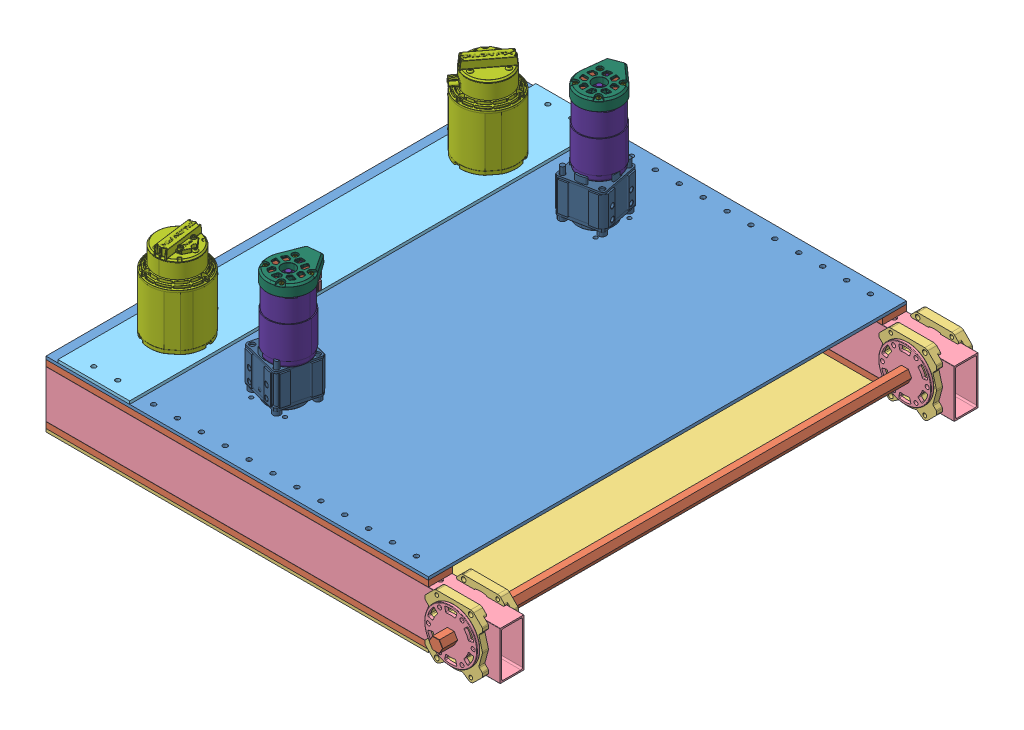
SolidWorks assembly ShooterAssem5, configuration Default. Lengths in mm.
Overall size (500 222.05 558.8).
72 component instances, 22 part files, 84 mates.
Components (placement in the parent):
- ShooterPlate5-1: ShooterPlate5 [Default] at (-92.3523 325.8959 643.1212) size (406.4 3.17 508)
- ThickStick-3: ThickStick [Default] at (-92.3523 262.3959 643.1212) size (406.4 6.35 25.4)
- ThickStick-1: ThickStick [Default] at (-92.3523 319.5459 643.1212) size (406.4 6.35 25.4)
- ThickStick-2: ThickStick [Default] at (-92.3523 262.3959 160.5212) size (406.4 6.35 25.4)
- ThickStick-4: ThickStick [Default] at (-92.3523 319.5459 160.5212) size (406.4 6.35 25.4)
- ShooterPlate4-1: ShooterPlate4 [Default] at (-257.4523 259.2209 643.1212) size (406.4 3.17 508)
- side-1: side [Default] at (364.8477 294.1459 147.8212) x (0 0 1) z (-1 0 0) size (25.4 50.8 482.6)
- side-2: side [Default] at (364.8477 294.1459 630.4212) x (0 0 1) z (-1 0 0) size (25.4 50.8 482.6)
- Motor support2-1: Motor support2 [Default] at (-41.5523 329.0709 389.1212) x (0 0 1) z (-1 0 0) size (508 3.17 76.2)
- am-4119 8mm Key Hub.step-1: am-4119 8mm Key Hub.step [Default] at (-49.7507 310.7834 262.3625) x (0.806664 0 -0.591011) z (0 1 0) size (58.55 52.17 25.4)
- am-4119 8mm Key Hub.step-2: am-4119 8mm Key Hub.step [Default] at (-13.8443 310.7834 526.4806) x (-0.998309 0 0.058123) z (0 1 0) size (58.55 52.17 25.4)
- Falcon 500.step-1: Falcon 500.step [Default] at (-41.5523 392.9959 224.0212) x (-0.923728 0 0.383049) z (0 -1 0) size (62.05 60 125.3)
- Falcon 500.step-2: Falcon 500.step [Default] at (-41.5523 392.9959 554.2212) x (0.381645 0 -0.924309) z (0 -1 0) size (62.05 60 125.3)
- 4in hex stealth wheel-1: 4in hex stealth wheel [Default] at (-41.5523 290.5093 554.2212) x (0 -1 0) z (-0.448819 0 0.893623) size (25.4 101.6 101.6)
  - 4in Wheel Intergreated Hub 500 HEX.STEP-1: 4in Wheel Intergreated Hub 500 HEX.STEP [Default] at origin size (25.4 92.71 92.71)
  - 4in Tread.STEP-1: 4in Tread.STEP [Default] at origin size (25.4 101.6 101.6)
- 4in hex stealth wheel-2: 4in hex stealth wheel [Default] at (72.733 290.5093 554.2466) x (0 -1 0) z (-0.5 0 0.866025) size (25.4 101.6 101.6)
  - 4in Wheel Intergreated Hub 500 HEX.STEP-1: 4in Wheel Intergreated Hub 500 HEX.STEP [Default] at origin size (25.4 92.71 92.71)
  - 4in Tread.STEP-1: 4in Tread.STEP [Default] at origin size (25.4 101.6 101.6)
- 4in hex stealth wheel-3: 4in hex stealth wheel [Default] at (72.7256 290.5093 224.0405) x (0 -1 0) z (0.194202 0 0.980962) size (25.4 101.6 101.6)
  - 4in Wheel Intergreated Hub 500 HEX.STEP-1: 4in Wheel Intergreated Hub 500 HEX.STEP [Default] at origin size (25.4 92.71 92.71)
  - 4in Tread.STEP-1: 4in Tread.STEP [Default] at origin size (25.4 101.6 101.6)
- 4in hex stealth wheel-4: 4in hex stealth wheel [Default] at (-41.5523 290.5093 224.0212) x (0 -1 0) z (0.108499 0 0.994097) size (25.4 101.6 101.6)
  - 4in Wheel Intergreated Hub 500 HEX.STEP-1: 4in Wheel Intergreated Hub 500 HEX.STEP [Default] at origin size (25.4 92.71 92.71)
  - 4in Tread.STEP-1: 4in Tread.STEP [Default] at origin size (25.4 101.6 101.6)
- 4-1 Banebots-1: 4-1 Banebots [Default] at (72.7475 371.6159 224.0202) x (-0.194202 0 -0.980962) z (0 -1 0) size (47.62 47.62 76.19)
- 4-1 Banebots-2: 4-1 Banebots [Default] at (72.7467 371.6159 554.2209) x (-0.969356 0 -0.245662) z (0 -1 0) size (47.62 47.62 76.19)
- 775pro.step-1: 775pro.step [Default] at (71.7936 373.6479 219.2017) x (-0.934395 0 0.356239) z (0 -1 0) size (44.99 55.15 90.45)
  - 217-6457-000 Rev2.step-1: 217-6457-000 Rev2.step [Default] at (0 0 -66.1) x (1 0 0) z (0 1 0) size (44.99 33.26 55.15)
    - 217-6457-900 Rev1.step-1: 217-6457-900 Rev1.step [Default] at (0 5.3622 0) x (-1 0 0.000693) z (0.000693 0 1) size (41.5 28.13 51.51)
      - 217-6457-901 Rev3_Instruction Config.step-1: 217-6457-901 Rev3_Instruction Config.step [Default] at origin size (41.5 2.36 51.5)
      - 30-45BBS Rev1_SHORTENED CONTACT.step-1: 30-45BBS Rev1_SHORTENED CONTACT.step [Default] at (3.95 14.4494 26.711) x (0 1 0) z (0 0 -1) size (26 3.6 2)
      - 30-45BBS Rev1_SHORTENED CONTACT.step-2: 30-45BBS Rev1_SHORTENED CONTACT.step [Default] at (-3.9748 14.4494 26.711) x (0 1 0) z (0 0 -1) size (26 3.6 2)
      - PA45XX-X Rev1.step-1: PA45XX-X Rev1.step [Default] at (-8.4198 2.3622 73.1531) x (0 1 0) z (-1 0 0) size (24.71 8.41 8.41)
      - PA45XX-X Rev1.step-2: PA45XX-X Rev1.step [Default] at (-0.495 2.3622 73.1531) x (0 1 0) z (-1 0 0) size (24.71 8.41 8.41)
    - 217-6457-001 Rev4.step-1: 217-6457-001 Rev4.step [Default] at origin size (41.49 7.8 41.49)
    - 217-6457-002 Rev7.step-1: 217-6457-002 Rev7.step [Default] at (0 0.05 0) size (44.99 11.5 55.15)
    - 217-9191-008 Rev1.step-1: 217-9191-008 Rev1.step [Default] at (81.4247 7.8 32.3804) x (-0.560945 0 -0.827853) z (0 1 0) size (4.2 4.2 11.81)
    - 217-9191-008 Rev1.step-2: 217-9191-008 Rev1.step [Default] at (32.3804 7.8 -81.4247) x (-0.827853 0 0.560945) z (0 1 0) size (4.2 4.2 11.81)
    - 217-9191-008 Rev1.step-3: 217-9191-008 Rev1.step [Default] at (-81.4247 7.8 -32.3804) x (0.560945 0 0.827853) z (0 1 0) size (4.2 4.2 11.81)
    - 217-9191-008 Rev1.step-4: 217-9191-008 Rev1.step [Default] at (-32.3804 7.8 81.4247) x (0.827853 0 -0.560945) z (0 1 0) size (4.2 4.2 11.81)
  - 217-4347-000 Rev2.step-1: 217-4347-000 Rev2.step [Default] x (0 0 -1) z (-1 0 0) size (88 44.3 44.3)
- 775pro.step-2: 775pro.step [Default] at (77.5101 373.6479 555.4281) x (-0.994351 0 0.106139) z (0 -1 0) size (44.99 55.15 90.45)
  - 217-6457-000 Rev2.step-1: 217-6457-000 Rev2.step [Default] at (0 0 -66.1) x (1 0 0) z (0 1 0) size (44.99 33.26 55.15)
    - 217-6457-900 Rev1.step-1: 217-6457-900 Rev1.step [Default] at (0 5.3622 0) x (-1 0 0.000693) z (0.000693 0 1) size (41.5 28.13 51.51)
      - 217-6457-901 Rev3_Instruction Config.step-1: 217-6457-901 Rev3_Instruction Config.step [Default] at origin size (41.5 2.36 51.5)
      - 30-45BBS Rev1_SHORTENED CONTACT.step-1: 30-45BBS Rev1_SHORTENED CONTACT.step [Default] at (3.95 14.4494 26.711) x (0 1 0) z (0 0 -1) size (26 3.6 2)
      - 30-45BBS Rev1_SHORTENED CONTACT.step-2: 30-45BBS Rev1_SHORTENED CONTACT.step [Default] at (-3.9748 14.4494 26.711) x (0 1 0) z (0 0 -1) size (26 3.6 2)
      - PA45XX-X Rev1.step-1: PA45XX-X Rev1.step [Default] at (-8.4198 2.3622 73.1531) x (0 1 0) z (-1 0 0) size (24.71 8.41 8.41)
      - PA45XX-X Rev1.step-2: PA45XX-X Rev1.step [Default] at (-0.495 2.3622 73.1531) x (0 1 0) z (-1 0 0) size (24.71 8.41 8.41)
    - 217-6457-001 Rev4.step-1: 217-6457-001 Rev4.step [Default] at origin size (41.49 7.8 41.49)
    - 217-6457-002 Rev7.step-1: 217-6457-002 Rev7.step [Default] at (0 0.05 0) size (44.99 11.5 55.15)
    - 217-9191-008 Rev1.step-1: 217-9191-008 Rev1.step [Default] at (81.4247 7.8 32.3804) x (-0.560945 0 -0.827853) z (0 1 0) size (4.2 4.2 11.81)
    - 217-9191-008 Rev1.step-2: 217-9191-008 Rev1.step [Default] at (32.3804 7.8 -81.4247) x (-0.827853 0 0.560945) z (0 1 0) size (4.2 4.2 11.81)
    - 217-9191-008 Rev1.step-3: 217-9191-008 Rev1.step [Default] at (-81.4247 7.8 -32.3804) x (0.560945 0 0.827853) z (0 1 0) size (4.2 4.2 11.81)
    - 217-9191-008 Rev1.step-4: 217-9191-008 Rev1.step [Default] at (-32.3804 7.8 81.4247) x (0.827853 0 -0.560945) z (0 1 0) size (4.2 4.2 11.81)
  - 217-4347-000 Rev2.step-1: 217-4347-000 Rev2.step [Default] x (0 0 -1) z (-1 0 0) size (88 44.3 44.3)
- 4in hex shaft-1: 4in hex shaft [Default] at (72.7477 330.8489 224.0212) x (0.752436 0 -0.658665) z (0 -1 0) size (14.66 12.7 101.6)
- 4in hex shaft-2: 4in hex shaft [Default] at (72.7477 330.8489 554.2212) x (-0.969356 0 -0.245662) z (0 -1 0) size (14.66 12.7 101.6)
- am-2986 FR8ZZ Hex Bearing.step-1: am-2986 FR8ZZ Hex Bearing.step [Default] at (72.7477 255.9925 554.2212) x (0.969356 0 0.245662) z (0 1 0) size (31.12 31.12 7.93)
- am-2986 FR8ZZ Hex Bearing.step-2: am-2986 FR8ZZ Hex Bearing.step [Default] at (72.7477 322.6675 554.2212) x (1 0 0) z (0 1 0) size (31.12 31.12 7.93)
- am-2986 FR8ZZ Hex Bearing.step-3: am-2986 FR8ZZ Hex Bearing.step [Default] at (72.7477 322.6675 224.0212) x (0.194202 0 0.980962) z (0 1 0) size (31.12 31.12 7.93)
- am-2986 FR8ZZ Hex Bearing.step-4: am-2986 FR8ZZ Hex Bearing.step [Default] at (72.7477 255.9925 224.0212) x (0.946639 0 0.322297) z (0 1 0) size (31.12 31.12 7.93)
- shooteraxle-1: shooteraxle [Default] at (347.36 295.7842 109.7212) size (14.66 12.7 558.8)
- VersaBlock V2 (217-6111).step-1: VersaBlock V2 (217-6111).step [Default] at (347.3674 295.7969 131.9462) x (1 0 0) z (0 0 -1) size (61.04 66.67 9.53)
- VersaBlock V2 (217-6111).step-2: VersaBlock V2 (217-6111).step [Default] at (347.3674 295.7969 614.5462) x (1 0 0) z (0 0 -1) size (61.04 66.67 9.53)
- VersaBlock V2 (217-6111).step-3: VersaBlock V2 (217-6111).step [Default] at (347.3674 295.7969 646.2962) x (-1 0 0) z (0 0 1) size (61.04 66.67 9.53)
- VersaBlock V2 (217-6111).step-4: VersaBlock V2 (217-6111).step [Default] at (347.3674 295.7969 163.6962) x (-1 0 0) z (0 0 1) size (61.04 66.67 9.53)
- 1_2” Hex Bore Aluminum VersaHub (217-2592).step-1: 1_2” Hex Bore Aluminum VersaHub (217-2592).step [Default] at (347.3674 295.7969 138.2962) x (0 0 -1) z (0.866025 -0.5 0) size (12.7 55.88 55.88)
- 1_2” Hex Bore Aluminum VersaHub (217-2592).step-2: 1_2” Hex Bore Aluminum VersaHub (217-2592).step [Default] at (347.3674 295.7969 157.3462) x (0 0 1) z (-0.866025 -0.5 0) size (12.7 55.88 55.88)
- 1_2” Hex Bore Aluminum VersaHub (217-2592).step-3: 1_2” Hex Bore Aluminum VersaHub (217-2592).step [Default] at (347.3674 295.7969 620.8962) x (0 0 -1) z (0.866025 0.5 0) size (12.7 55.88 55.88)
- 1_2” Hex Bore Aluminum VersaHub (217-2592).step-4: 1_2” Hex Bore Aluminum VersaHub (217-2592).step [Default] at (347.3674 295.7969 639.9462) x (0 0 1) z (-0.866025 0.5 0) size (12.7 55.88 55.88)
Mates (geometry in assembly coordinates):
- Coincident2: coincident aligned: plane of ShooterPlate5-1 through (-92.3523 329.0709 643.1212) normal (-1 0 0); plane of side-2 through (-92.3523 319.2919 642.8672) normal (-1 0 0)
- Coincident3: coincident aligned: plane of ShooterPlate5-1 through (-92.3523 329.0709 643.1212) normal (0 0 1); plane of side-2 through (390.2477 319.2919 643.1212) normal (0 0 1)
- Coincident4: coincident anti-aligned: plane of ShooterPlate5-1 through (-92.3523 325.8959 643.1212) normal (0 -1 0); plane of ThickStick-1 through (-92.3523 325.8959 643.1212) normal (0 1 0)
- Coincident5: coincident aligned: plane of ShooterPlate5-1 through (314.0477 329.0709 643.1212) normal (1 0 0); plane of ThickStick-1 through (314.0477 325.8959 643.1212) normal (1 0 0)
- Coincident6: coincident aligned: plane of ShooterPlate5-1 through (-92.3523 329.0709 643.1212) normal (0 0 1); plane of ThickStick-1 through (-92.3523 325.8959 643.1212) normal (0 0 1)
- Coincident7: coincident anti-aligned: plane of ThickStick-1 through (-92.3523 319.5459 643.1212) normal (0 -1 0); plane of side-2 through (390.2477 319.5459 617.9752) normal (0 1 0)
- Coincident8: coincident anti-aligned: plane of ThickStick-3 through (-92.3523 268.7459 643.1212) normal (0 1 0); plane of side-2 through (390.2477 268.7459 642.8672) normal (0 -1 0)
- Coincident9: coincident aligned: plane of ThickStick-3 through (-92.3523 268.7459 643.1212) normal (0 0 1); plane of side-2 through (390.2477 319.2919 643.1212) normal (0 0 1)
- Coincident11: coincident aligned: plane of ThickStick-1 through (-92.3523 325.8959 643.1212) normal (-1 0 0); plane of ThickStick-3 through (-92.3523 268.7459 643.1212) normal (-1 0 0)
- Coincident12: coincident anti-aligned: plane of ThickStick-3 through (-92.3523 262.3959 643.1212) normal (0 -1 0); plane of ShooterPlate4-1 through (-257.4523 262.3959 643.1212) normal (0 1 0)
- Coincident13: coincident aligned: plane of ShooterPlate5-1 through (-92.3523 329.0709 643.1212) normal (0 0 1); plane of ShooterPlate4-1 through (-257.4523 262.3959 643.1212) normal (0 0 1)
- Coincident14: coincident aligned: plane of ThickStick-3 through (314.0477 268.7459 643.1212) normal (1 0 0); plane of ShooterPlate4-1 through (314.0477 262.3959 643.1212) normal (1 0 0)
- Coincident15: coincident anti-aligned: plane of ShooterPlate5-1 through (-92.3523 325.8959 643.1212) normal (0 -1 0); plane of ThickStick-4 through (-92.3523 325.8959 160.5212) normal (0 1 0)
- Coincident16: coincident aligned: plane of ShooterPlate5-1 through (-92.3523 329.0709 643.1212) normal (-1 0 0); plane of ThickStick-4 through (-92.3523 325.8959 160.5212) normal (-1 0 0)
- Coincident17: coincident anti-aligned: plane of ThickStick-4 through (-92.3523 319.5459 160.5212) normal (0 -1 0); plane of side-1 through (390.2477 319.5459 135.3752) normal (0 1 0)
- Coincident18: coincident aligned: plane of ShooterPlate5-1 through (-92.3523 329.0709 135.1212) normal (0 0 -1); plane of ThickStick-4 through (-92.3523 325.8959 135.1212) normal (0 0 -1)
- Coincident19: coincident aligned: plane of ThickStick-4 through (-92.3523 325.8959 135.1212) normal (0 0 -1); plane of side-1 through (390.2477 268.9999 135.1212) normal (0 0 -1)
- Coincident20: coincident aligned: plane of ThickStick-4 through (-92.3523 325.8959 160.5212) normal (-1 0 0); plane of side-1 through (-92.3523 319.2919 160.2672) normal (-1 0 0)
- Coincident21: coincident anti-aligned: plane of ThickStick-2 through (-92.3523 262.3959 160.5212) normal (0 -1 0); plane of ShooterPlate4-1 through (-257.4523 262.3959 643.1212) normal (0 1 0)
- Coincident22: coincident aligned: plane of ThickStick-2 through (-92.3523 268.7459 135.1212) normal (0 0 -1); plane of side-1 through (390.2477 268.9999 135.1212) normal (0 0 -1)
- Coincident23: coincident aligned: plane of ShooterPlate5-1 through (-92.3523 329.0709 643.1212) normal (-1 0 0); plane of ThickStick-2 through (-92.3523 268.7459 160.5212) normal (-1 0 0)
- Coincident24: coincident anti-aligned: plane of ShooterPlate5-1 through (-92.3523 329.0709 643.1212) normal (0 1 0); plane of Motor support2-1 through (-41.5523 329.0709 389.1212) normal (0 -1 0)
- Coincident25: coincident aligned: plane of side-1 through (390.2477 268.9999 135.1212) normal (0 0 -1); plane of Motor support2-1 through (-79.6523 332.2459 135.1212) normal (0 0 -1)
- Concentric1: concentric aligned: cylinder of ShooterPlate5-1 through (-41.5523 325.8959 224.0212) axis (0 1 0) radius 14.2875; cylinder of Motor support2-1 through (-41.5523 329.0709 224.0212) axis (0 1 0) radius 12.7
- Concentric5: concentric anti-aligned: cylinder of Motor support2-1 through (-41.5523 329.0709 224.0212) axis (0 1 0) radius 12.7; cylinder of am-4119 8mm Key Hub.step-1 through (-41.5523 326.6584 224.0212) axis (0 -1 0) radius 11.1125
- Coincident30: coincident anti-aligned: plane of am-4119 8mm Key Hub.step-1 through (-41.5523 304.4334 224.0212) normal (0 -1 0); plane of 4in hex stealth wheel-4/4in Wheel Intergreated Hub 500 HEX.STEP-1 through (-35.2398 304.4334 223.3322) normal (0 1 0)
- Concentric6: concentric anti-aligned: cylinder of am-4119 8mm Key Hub.step-1 through (-60.761 310.7834 238.0946) axis (0 -1 0) radius 2.5527; cylinder of 4in hex stealth wheel-4/4in Wheel Intergreated Hub 500 HEX.STEP-1 through (-60.761 279.0334 238.0946) axis (0 1 0) radius 2.0193
- Concentric7: concentric anti-aligned: cylinder of am-4119 8mm Key Hub.step-1 through (-38.9687 310.7834 247.6931) axis (0 -1 0) radius 2.5527; cylinder of 4in hex stealth wheel-4/4in Wheel Intergreated Hub 500 HEX.STEP-1 through (-38.9687 279.0334 247.6931) axis (0 1 0) radius 2.0193
- Coincident31: coincident anti-aligned: plane of am-4119 8mm Key Hub.step-2 through (-41.5523 304.4334 554.2212) normal (0 -1 0); plane of 4in hex stealth wheel-1/4in Wheel Intergreated Hub 500 HEX.STEP-1 through (-35.8778 304.4334 557.0712) normal (0 1 0)
- Concentric8: concentric anti-aligned: cylinder of am-4119 8mm Key Hub.step-2 through (-65.3245 310.7834 555.6052) axis (0 -1 0) radius 2.5527; cylinder of 4in hex stealth wheel-1/4in Wheel Intergreated Hub 500 HEX.STEP-1 through (-65.3245 279.0334 555.6052) axis (0 1 0) radius 2.0193
- Concentric9: concentric anti-aligned: cylinder of am-4119 8mm Key Hub.step-2 through (-52.2398 310.7834 575.5005) axis (0 -1 0) radius 2.5527; cylinder of 4in hex stealth wheel-1/4in Wheel Intergreated Hub 500 HEX.STEP-1 through (-52.2398 279.0334 575.5005) axis (0 1 0) radius 2.0193
- Concentric10: concentric anti-aligned: cylinder of ShooterPlate5-1 through (72.7477 325.8959 224.0212) axis (0 1 0) radius 14.2875; cylinder of am-2986 FR8ZZ Hex Bearing.step-3 through (72.7477 330.5949 224.0212) axis (0 -1 0) radius 14.2875
- Coincident39: coincident anti-aligned: plane of ShooterPlate5-1 through (-92.3523 329.0709 643.1212) normal (0 1 0); plane of am-2986 FR8ZZ Hex Bearing.step-3 through (75.4607 329.0709 237.7252) normal (0 -1 0)
- Concentric11: concentric anti-aligned: cylinder of ShooterPlate5-1 through (72.7477 325.8959 554.2212) axis (0 1 0) radius 14.2875; cylinder of am-2986 FR8ZZ Hex Bearing.step-2 through (72.7477 330.5949 554.2212) axis (0 -1 0) radius 14.2875
- Coincident40: coincident anti-aligned: plane of ShooterPlate5-1 through (-92.3523 329.0709 643.1212) normal (0 1 0); plane of am-2986 FR8ZZ Hex Bearing.step-2 through (86.7177 329.0709 554.2212) normal (0 -1 0)
- Concentric12: concentric anti-aligned: cylinder of ShooterPlate4-1 through (72.7477 259.2209 554.2212) axis (0 1 0) radius 14.2875; cylinder of am-2986 FR8ZZ Hex Bearing.step-1 through (72.7477 263.9199 554.2212) axis (0 -1 0) radius 14.2875
- Coincident41: coincident anti-aligned: plane of ShooterPlate4-1 through (-257.4523 262.3959 643.1212) normal (0 1 0); plane of am-2986 FR8ZZ Hex Bearing.step-1 through (86.2896 262.3959 557.6531) normal (0 -1 0)
- Concentric13: concentric anti-aligned: cylinder of ShooterPlate4-1 through (72.7477 259.2209 224.0212) axis (0 1 0) radius 14.2875; cylinder of am-2986 FR8ZZ Hex Bearing.step-4 through (72.7477 263.9199 224.0212) axis (0 -1 0) radius 14.2875
- Coincident42: coincident anti-aligned: plane of ShooterPlate4-1 through (-257.4523 262.3959 643.1212) normal (0 1 0); plane of am-2986 FR8ZZ Hex Bearing.step-4 through (85.9723 262.3959 228.5236) normal (0 -1 0)
- Coincident44: coincident anti-aligned: plane of 4-1 Banebots-1 through (67.2306 330.8559 228.8507) normal (-0.980962 0 0.194202); plane of am-2986 FR8ZZ Hex Bearing.step-3 through (67.2306 330.5949 228.8507) normal (0.980962 0 -0.194202)
- Coincident49: coincident aligned: plane of 4in hex stealth wheel-3/4in Wheel Intergreated Hub 500 HEX.STEP-1 through (78.9547 304.4334 222.8073) normal (0 1 0); plane of 4in hex stealth wheel-4/4in Wheel Intergreated Hub 500 HEX.STEP-1 through (-35.2398 304.4334 223.3322) normal (0 1 0)
- Coincident50: coincident aligned: plane of 4in hex stealth wheel-1/4in Wheel Intergreated Hub 500 HEX.STEP-1 through (-35.8778 304.4334 557.0712) normal (0 1 0); plane of 4in hex stealth wheel-2/4in Wheel Intergreated Hub 500 HEX.STEP-1 through (78.2323 304.4334 557.4216) normal (0 1 0)
- Coincident53: coincident anti-aligned: plane of 4in hex shaft-2 through (67.6339 229.2489 559.4759) normal (-0.245662 0 0.969356); plane of am-2986 FR8ZZ Hex Bearing.step-1 through (74.7416 263.9199 561.2772) normal (0.245662 0 -0.969356)
- Coincident54: coincident anti-aligned: plane of 4in hex shaft-2 through (65.6401 229.2489 552.4199) normal (-0.962318 0 0.271928); plane of am-2986 FR8ZZ Hex Bearing.step-1 through (67.6339 263.9199 559.4759) normal (0.962318 0 -0.271928)
- Tangent9: tangent: plane of assembly; face of 4-1 Banebots-2; plane of 4in hex shaft-2 through (72.7477 330.8489 554.2212) normal (0 1 0)
- Coincident55: coincident aligned: plane of 4-1 Banebots-2 through (65.6401 330.8559 552.4199) normal (-0.716656 0 -0.697427); plane of 4in hex shaft-2 through (70.7538 229.2489 547.1651) normal (-0.716656 0 -0.697427)
- Coincident56: coincident aligned: plane of 4-1 Banebots-2 through (70.7538 330.8559 547.1651) normal (0.245662 0 -0.969356); plane of 4in hex shaft-2 through (77.8615 229.2489 548.9664) normal (0.245662 0 -0.969356)
- Tangent10: tangent: plane of assembly; face of 4-1 Banebots-2; plane of am-2986 FR8ZZ Hex Bearing.step-2 through (88.3052 330.5949 554.2212) normal (0 1 0)
- Tangent11: tangent: plane of assembly; face of 4-1 Banebots-1; plane of 4in hex shaft-1 through (72.7477 330.8489 224.0212) normal (0 1 0)
- Coincident57: coincident aligned: plane of 4-1 Banebots-1 through (65.8066 330.8559 221.658) normal (-0.658665 0 -0.752436); plane of 4in hex shaft-1 through (71.3238 229.2489 216.8284) normal (-0.658665 0 -0.752436)
- Coincident58: coincident aligned: plane of 4-1 Banebots-1 through (67.2306 330.8559 228.8507) normal (-0.980962 0 0.194202); plane of 4in hex shaft-1 through (65.8066 229.2489 221.658) normal (-0.980962 0 0.194202)
- Tangent12: tangent: plane of assembly; face of 4-1 Banebots-1; plane of am-2986 FR8ZZ Hex Bearing.step-3 through (75.769 330.5949 239.2825) normal (0 1 0)
- Coincident60: coincident anti-aligned: plane of 4in hex shaft-1 through (79.6888 229.2489 226.3843) normal (0.980962 0 -0.194202); plane of am-2986 FR8ZZ Hex Bearing.step-4 through (78.2648 263.9199 219.1916) normal (-0.980962 0 0.194202)
- Coincident61: coincident anti-aligned: plane of 4in hex shaft-1 through (74.1717 229.2489 231.2139) normal (0.658665 0 0.752436); plane of am-2986 FR8ZZ Hex Bearing.step-4 through (79.6888 263.9199 226.3843) normal (-0.658665 0 -0.752436)
- Coincident62: coincident anti-aligned: plane of 4in hex stealth wheel-3/4in Wheel Intergreated Hub 500 HEX.STEP-1 through (71.296 304.4334 216.819) normal (-0.322297 0 0.946639); plane of 4in hex shaft-1 through (78.2648 229.2489 219.1916) normal (0.322297 0 -0.946639)
- Coincident63: coincident anti-aligned: plane of 4in hex stealth wheel-3/4in Wheel Intergreated Hub 500 HEX.STEP-1 through (78.2648 304.4334 219.1916) normal (-0.980962 0 0.194202); plane of 4in hex shaft-1 through (79.6888 229.2489 226.3843) normal (0.980962 0 -0.194202)
- Distance1: distance = 25.4 mm: plane of side-1 through (390.2477 268.9999 135.1212) normal (0 0 -1); plane of shooteraxle-1 through (347.36 295.7842 109.7212) normal (0 0 -1)
- Coincident72: coincident anti-aligned: plane of side-2 through (390.2477 319.2919 643.1212) normal (0 0 1); plane of VersaBlock V2 (217-6111).step-3 through (347.3674 295.7969 643.1212) normal (0 0 -1)
- Coincident73: coincident anti-aligned: plane of side-2 through (390.2477 268.7459 642.8672) normal (0 -1 0); plane of VersaBlock V2 (217-6111).step-3 through (316.8493 268.7459 722.6131) normal (0 1 0)
- Tangent13: tangent aligned: cylinder of side-2 through (345.7977 295.9239 643.1212) axis (0 0 -1) radius 12.7; cylinder of VersaBlock V2 (217-6111).step-3 through (347.3674 295.7969 604.2621) axis (0 0 1) radius 14.2748
- Coincident74: coincident anti-aligned: plane of side-2 through (390.2477 268.9999 617.7212) normal (0 0 -1); plane of VersaBlock V2 (217-6111).step-2 through (347.3674 295.7969 617.7212) normal (0 0 1)
- Coincident75: coincident anti-aligned: plane of side-2 through (390.2477 268.7459 642.8672) normal (0 -1 0); plane of VersaBlock V2 (217-6111).step-2 through (377.8855 268.7459 538.2292) normal (0 1 0)
- Concentric24: concentric anti-aligned: cylinder of VersaBlock V2 (217-6111).step-2 through (365.4542 323.1543 620.8962) axis (0 0 1) radius 2.0193; cylinder of VersaBlock V2 (217-6111).step-3 through (365.4542 323.1543 639.9462) axis (0 0 -1) radius 2.4892
- Coincident76: coincident anti-aligned: plane of side-1 through (390.2477 268.9999 135.1212) normal (0 0 -1); plane of VersaBlock V2 (217-6111).step-1 through (347.3674 295.7969 135.1212) normal (0 0 1)
- Coincident77: coincident anti-aligned: plane of side-1 through (390.2477 268.7459 160.2672) normal (0 -1 0); plane of VersaBlock V2 (217-6111).step-1 through (377.8855 268.7459 55.6292) normal (0 1 0)
- Tangent14: tangent aligned: cylinder of side-1 through (345.7977 295.9239 160.5212) axis (0 0 -1) radius 12.7; cylinder of VersaBlock V2 (217-6111).step-1 through (347.3674 295.7969 173.9802) axis (0 0 -1) radius 14.2748
- Coincident78: coincident anti-aligned: plane of side-1 through (390.2477 268.7459 160.2672) normal (0 -1 0); plane of VersaBlock V2 (217-6111).step-4 through (316.8493 268.7459 240.0131) normal (0 1 0)
- Coincident79: coincident anti-aligned: plane of side-1 through (390.2477 319.2919 160.5212) normal (0 0 1); plane of VersaBlock V2 (217-6111).step-4 through (347.3674 295.7969 160.5212) normal (0 0 -1)
- Concentric26: concentric anti-aligned: cylinder of VersaBlock V2 (217-6111).step-1 through (365.4542 323.1543 138.2962) axis (0 0 1) radius 2.0193; cylinder of VersaBlock V2 (217-6111).step-4 through (365.4542 323.1543 157.3462) axis (0 0 -1) radius 2.4892
- Coincident80: coincident anti-aligned: plane of VersaBlock V2 (217-6111).step-3 through (359.2736 316.4191 649.4712) normal (0 0 1); plane of 1_2” Hex Bore Aluminum VersaHub (217-2592).step-4 through (354.5148 308.1766 649.4712) normal (0 0 -1)
- Concentric30: concentric aligned: cylinder of VersaBlock V2 (217-6111).step-3 through (335.4611 316.4191 649.4712) axis (0 0 1) radius 1.7272; cylinder of 1_2” Hex Bore Aluminum VersaHub (217-2592).step-4 through (335.4611 316.4191 566.8528) axis (0 0 1) radius 2.15
- Concentric31: concentric aligned: cylinder of VersaBlock V2 (217-6111).step-3 through (359.2736 316.4191 649.4712) axis (0 0 1) radius 1.7272; cylinder of 1_2” Hex Bore Aluminum VersaHub (217-2592).step-4 through (359.2736 316.4191 566.8528) axis (0 0 1) radius 2.15
- Coincident82: coincident anti-aligned: plane of VersaBlock V2 (217-6111).step-1 through (335.4611 316.4191 128.7712) normal (0 0 -1); plane of 1_2” Hex Bore Aluminum VersaHub (217-2592).step-1 through (354.5148 308.1766 128.7712) normal (0 0 1)
- Concentric32: concentric aligned: cylinder of VersaBlock V2 (217-6111).step-1 through (335.4611 316.4191 128.7712) axis (0 0 -1) radius 1.7272; cylinder of 1_2” Hex Bore Aluminum VersaHub (217-2592).step-1 through (335.4611 316.4191 211.3895) axis (0 0 -1) radius 2.15
- Concentric33: concentric aligned: cylinder of VersaBlock V2 (217-6111).step-1 through (359.2736 316.4191 128.7712) axis (0 0 -1) radius 1.7272; cylinder of 1_2” Hex Bore Aluminum VersaHub (217-2592).step-1 through (359.2736 316.4191 211.3895) axis (0 0 -1) radius 2.15
- Coincident83: coincident anti-aligned: plane of VersaBlock V2 (217-6111).step-4 through (359.2736 316.4191 166.8712) normal (0 0 1); plane of 1_2” Hex Bore Aluminum VersaHub (217-2592).step-2 through (340.2199 308.1766 166.8712) normal (0 0 -1)
- Concentric35: concentric aligned: cylinder of VersaBlock V2 (217-6111).step-4 through (359.2736 316.4191 166.8712) axis (0 0 1) radius 1.7272; cylinder of 1_2” Hex Bore Aluminum VersaHub (217-2592).step-2 through (359.2736 316.4191 84.2528) axis (0 0 1) radius 2.15
- Concentric36: concentric aligned: cylinder of VersaBlock V2 (217-6111).step-4 through (335.4611 316.4191 166.8712) axis (0 0 1) radius 1.7272; cylinder of 1_2” Hex Bore Aluminum VersaHub (217-2592).step-2 through (335.4611 316.4191 84.2528) axis (0 0 1) radius 2.15
- Coincident84: coincident anti-aligned: plane of VersaBlock V2 (217-6111).step-2 through (335.4611 316.4191 611.3712) normal (0 0 -1); plane of 1_2” Hex Bore Aluminum VersaHub (217-2592).step-3 through (340.2199 308.1766 611.3712) normal (0 0 1)
- Concentric37: concentric aligned: cylinder of VersaBlock V2 (217-6111).step-2 through (359.2736 316.4191 611.3712) axis (0 0 -1) radius 1.7272; cylinder of 1_2” Hex Bore Aluminum VersaHub (217-2592).step-3 through (359.2736 316.4191 693.9895) axis (0 0 -1) radius 2.15
- Concentric38: concentric aligned: cylinder of VersaBlock V2 (217-6111).step-2 through (335.4611 316.4191 611.3712) axis (0 0 -1) radius 1.7272; cylinder of 1_2” Hex Bore Aluminum VersaHub (217-2592).step-3 through (335.4611 316.4191 693.9895) axis (0 0 -1) radius 2.15
- Coincident85: coincident anti-aligned: plane of shooteraxle-1 through (351.0262 289.4342 668.5212) normal (0 -1 0); plane of 1_2” Hex Bore Aluminum VersaHub (217-2592).step-4 through (343.6939 289.4342 639.9462) normal (0 1 0)
- Coincident86: coincident anti-aligned: plane of shooteraxle-1 through (343.6939 289.4342 668.5212) normal (-0.866025 -0.5 0); plane of 1_2” Hex Bore Aluminum VersaHub (217-2592).step-4 through (340.0204 295.7969 639.9462) normal (0.866025 0.5 0)
- Distance2: distance = 25.4 mm: plane of shooteraxle-1 through (347.36 295.7842 668.5212) normal (0 0 1); plane of side-2 through (390.2477 319.2919 643.1212) normal (0 0 1)
